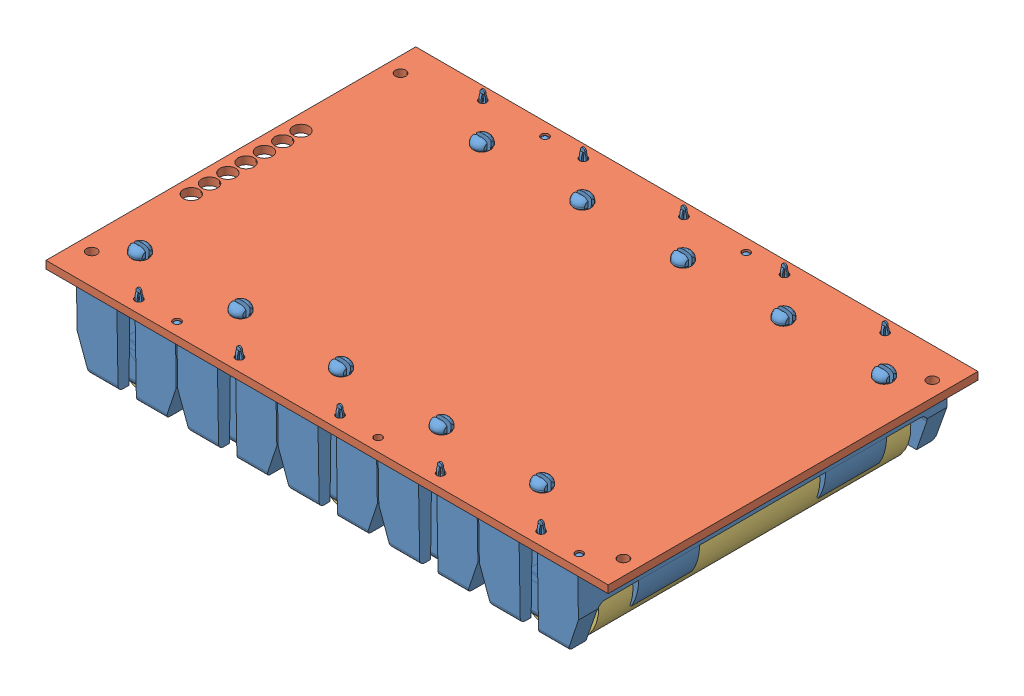
SolidWorks assembly PCB_Battery Assembly, configuration Default. Lengths in mm.
Overall size (117.17 24.87 77.22).
11 component instances, 3 part files, 25 mates.
Components (placement in the parent):
- Battery Holder - keystone-PN1043-1: Battery Holder - keystone-PN1043 [Default] at (-125.3925 103.3982 18.9155) x (1 0 0) z (0 0 -1) size (20.65 18.93 77.14)
- Battery PCB-1: Battery PCB [Default] at (-148.3186 115.135 -16.9005) x (1 0 0) z (0 -1 0) size (117.17 77.06 1.59)
- battery_6612-1: battery_6612 [Default] at (-117.0385 104.4035 -11.3639) x (-0.413992 0.91028 0) z (0.91028 0.413992 0) size (18.3 65.05 18.3)
- battery_6612-2: battery_6612 [Default] at (-137.9935 104.4035 54.6265) x (-0.916106 0.400937 0) z (-0.400937 -0.916106 0) size (18.3 65.05 18.3)
- Battery Holder - keystone-PN1043-2: Battery Holder - keystone-PN1043 [Default] at (-129.6396 103.3982 24.3471) x (-1 0 0) z (0 0 1) size (20.65 18.93 77.14)
- Battery Holder - keystone-PN1043-3: Battery Holder - keystone-PN1043 [Default] at (-104.4375 103.3982 18.9155) x (1 0 0) z (0 0 -1) size (20.65 18.93 77.14)
- battery_6612-3: battery_6612 [Default] at (-96.0835 104.4035 -10.3735) x (1 0 0) z (0 -1 0) size (18.3 65.05 18.3)
- Battery Holder - keystone-PN1043-4: Battery Holder - keystone-PN1043 [Default] at (-83.4825 103.3982 18.9155) x (1 0 0) z (0 0 -1) size (20.65 18.93 77.14)
- Battery Holder - keystone-PN1043-5: Battery Holder - keystone-PN1043 [Default] at (-45.8196 103.3982 24.3471) x (-1 0 0) z (0 0 1) size (20.65 18.93 77.14)
- battery_6612-4: battery_6612 [Default] at (-75.1285 104.4035 -11.3639) x (-0.923728 -0.383049 0) z (-0.383049 0.923728 0) size (18.3 65.05 18.3)
- battery_6612-5: battery_6612 [Default] at (-54.1735 104.4035 54.6265) x (-1 0 0) z (0 -1 0) size (18.3 65.05 18.3)
Mates (geometry in assembly coordinates):
- Concentric1: concentric anti-aligned: cylinder of Battery Holder - keystone-PN1043-1 through (-117.0385 104.4035 -12.8111) axis (0 0 1) radius 9.144; cylinder of battery_6612-1 through (-117.0385 104.4035 53.6861) axis (0 0 -1) radius 9.15
- Coincident2: coincident anti-aligned: plane of Battery Holder - keystone-PN1043-1 through (-113.8635 103.7431 53.6861) normal (0 0 -1); plane of battery_6612-1 through (-117.0385 104.4035 53.6861) normal (0 0 1)
- Concentric4: concentric anti-aligned: cylinder of Battery Holder - keystone-PN1043-3 through (-96.0835 104.4035 -12.8111) axis (0 0 1) radius 9.144; cylinder of battery_6612-3 through (-96.0835 104.4035 54.6765) axis (0 0 -1) radius 9.15
- Coincident4: coincident anti-aligned: plane of Battery Holder - keystone-PN1043-3 through (-99.2585 103.7431 -10.3735) normal (0 0 1); plane of battery_6612-3 through (-96.0835 104.4035 -10.3735) normal (0 0 -1)
- Concentric5: concentric anti-aligned: cylinder of battery_6612-2 through (-137.9935 104.4035 -10.4235) axis (0 0 1) radius 9.15; cylinder of Battery Holder - keystone-PN1043-2 through (-137.9935 104.4035 56.0737) axis (0 0 -1) radius 9.144
- Coincident5: coincident anti-aligned: plane of battery_6612-2 through (-137.9935 104.4035 -10.4235) normal (0 0 -1); plane of Battery Holder - keystone-PN1043-2 through (-141.1685 103.7431 -10.4235) normal (0 0 1)
- Concentric12: concentric anti-aligned: cylinder of Battery PCB-1 through (-145.9945 113.5475 49.2538) axis (0 1 0) radius 1.7145; cylinder of Battery Holder - keystone-PN1043-2 through (-145.9945 113.5475 49.2538) axis (0 -1 0) radius 1.4605
- Coincident9: coincident aligned: plane of Battery PCB-1 through (-148.3186 113.5475 -16.9005) normal (0 -1 0); plane of Battery Holder - keystone-PN1043-2 through (-127.6684 113.5475 56.0737) normal (0 -1 0)
- Concentric13: concentric anti-aligned: cylinder of Battery PCB-1 through (-129.9925 113.5475 -5.9912) axis (0 1 0) radius 1.7145; cylinder of Battery Holder - keystone-PN1043-2 through (-129.9925 113.5475 -5.9912) axis (0 -1 0) radius 1.4605
- Coincident10: coincident aligned: plane of Battery Holder - keystone-PN1043-1 through (-127.3636 113.5475 -12.8111) normal (0 -1 0); plane of Battery PCB-1 through (-148.3186 113.5475 -16.9005) normal (0 -1 0)
- Concentric14: concentric anti-aligned: cylinder of Battery Holder - keystone-PN1043-1 through (-125.0395 113.5475 49.2538) axis (0 -1 0) radius 1.4605; cylinder of Battery PCB-1 through (-125.0395 113.5475 49.2538) axis (0 1 0) radius 1.7145
- Concentric15: concentric anti-aligned: cylinder of Battery Holder - keystone-PN1043-1 through (-109.0375 113.5475 -5.9912) axis (0 -1 0) radius 1.4605; cylinder of Battery PCB-1 through (-109.0375 113.5475 -5.9912) axis (0 1 0) radius 1.7145
- Coincident11: coincident aligned: plane of Battery PCB-1 through (-148.3186 113.5475 -16.9005) normal (0 -1 0); plane of Battery Holder - keystone-PN1043-3 through (-106.4086 113.5475 -12.8111) normal (0 -1 0)
- Concentric16: concentric anti-aligned: cylinder of Battery PCB-1 through (-104.0845 113.5475 49.2538) axis (0 1 0) radius 1.7145; cylinder of Battery Holder - keystone-PN1043-3 through (-104.0845 113.5475 49.2538) axis (0 -1 0) radius 1.4605
- Concentric17: concentric anti-aligned: cylinder of Battery PCB-1 through (-88.0825 113.5475 -5.9912) axis (0 1 0) radius 1.7145; cylinder of Battery Holder - keystone-PN1043-3 through (-88.0825 113.5475 -5.9912) axis (0 -1 0) radius 1.4605
- Concentric19: concentric anti-aligned: cylinder of Battery Holder - keystone-PN1043-5 through (-54.1735 104.4035 56.0737) axis (0 0 -1) radius 9.144; cylinder of battery_6612-5 through (-54.1735 104.4035 -10.4235) axis (0 0 1) radius 9.15
- Coincident13: coincident anti-aligned: plane of Battery Holder - keystone-PN1043-5 through (-57.3485 103.7431 -10.4235) normal (0 0 1); plane of battery_6612-5 through (-54.1735 104.4035 -10.4235) normal (0 0 -1)
- Concentric20: concentric anti-aligned: cylinder of Battery Holder - keystone-PN1043-4 through (-75.1285 104.4035 -12.8111) axis (0 0 1) radius 9.144; cylinder of battery_6612-4 through (-75.1285 104.4035 53.6861) axis (0 0 -1) radius 9.15
- Coincident14: coincident anti-aligned: plane of Battery Holder - keystone-PN1043-4 through (-71.9535 103.7431 53.6861) normal (0 0 -1); plane of battery_6612-4 through (-75.1285 104.4035 53.6861) normal (0 0 1)
- Coincident15: coincident aligned: plane of Battery PCB-1 through (-148.3186 113.5475 -16.9005) normal (0 -1 0); plane of Battery Holder - keystone-PN1043-4 through (-85.4536 113.5475 -12.8111) normal (0 -1 0)
- Concentric21: concentric anti-aligned: cylinder of Battery PCB-1 through (-83.1295 113.5475 49.2538) axis (0 1 0) radius 1.7145; cylinder of Battery Holder - keystone-PN1043-4 through (-83.1295 113.5475 49.2538) axis (0 -1 0) radius 1.4605
- Concentric22: concentric anti-aligned: cylinder of Battery PCB-1 through (-67.1275 113.5475 -5.9912) axis (0 1 0) radius 1.7145; cylinder of Battery Holder - keystone-PN1043-4 through (-67.1275 113.5475 -5.9912) axis (0 -1 0) radius 1.4605
- Coincident16: coincident aligned: plane of Battery PCB-1 through (-148.3186 113.5475 -16.9005) normal (0 -1 0); plane of Battery Holder - keystone-PN1043-5 through (-43.8484 113.5475 56.0737) normal (0 -1 0)
- Concentric23: concentric anti-aligned: cylinder of Battery Holder - keystone-PN1043-5 through (-62.1745 113.5475 49.2538) axis (0 -1 0) radius 1.4605; cylinder of Battery PCB-1 through (-62.1745 113.5475 49.2538) axis (0 1 0) radius 1.7145
- Concentric24: concentric anti-aligned: cylinder of Battery PCB-1 through (-46.1725 113.5475 -5.9912) axis (0 1 0) radius 1.7145; cylinder of Battery Holder - keystone-PN1043-5 through (-46.1725 113.5475 -5.9912) axis (0 -1 0) radius 1.4605
